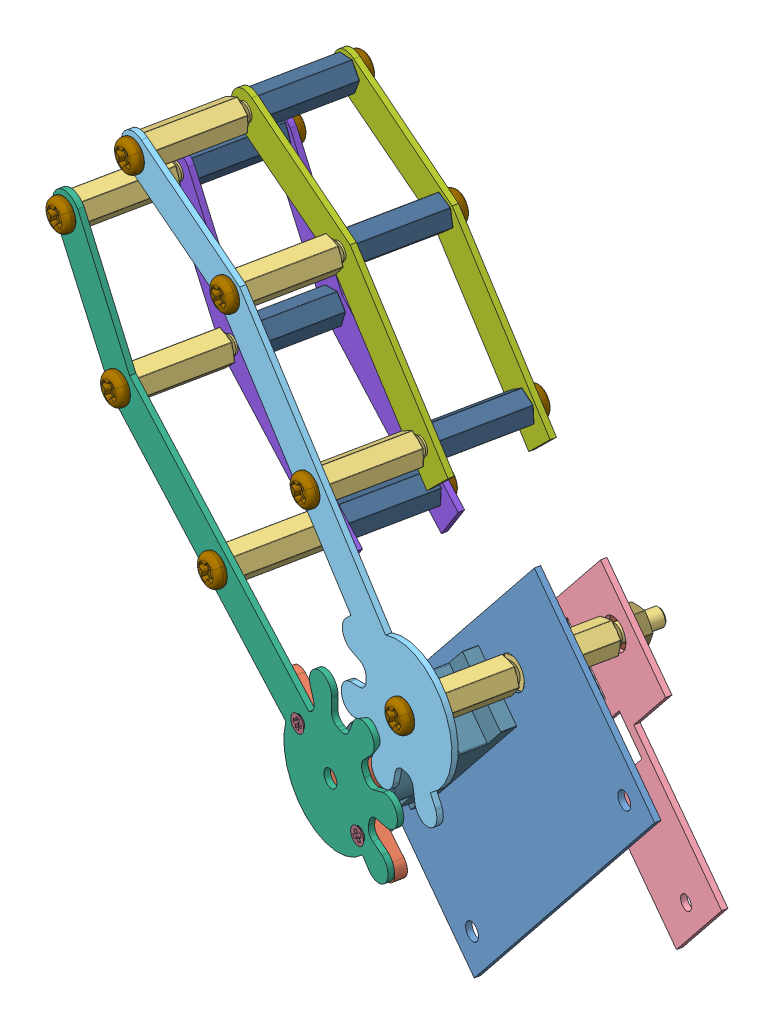
SolidWorks assembly Gripper, configuration Predeterminado. Lengths in mm.
Overall size (316.11 321.65 221.82).
47 component instances, 15 part files, 68 mates.
Components (placement in the parent):
- GripperBase-1: GripperBase [Predeterminado] at (70.7355 47.6147 -44.2967) x (-0.635673 -0.762927 -0.117736) z (-0.190799 0.007493 0.981601) size (64 37 1)
- Microservo horn-1: Microservo horn [По умолчанию] at (52.0643 33.1861 -30.7009) x (0.809028 -0.565128 0.161569) z (0.190799 -0.007493 -0.981601) size (32 7.5 5)
- HTSB-M3-15-5-2-2: HTSB-M3-15-5-2 [Predeterminado] at (71.8352 53.3676 -42.2931) x (-0.38875 0.917636 -0.082568) z (0.190799 -0.007493 -0.981601) size (5.74 5 23)
- HTSB-M3-15-5-2-3: HTSB-M3-15-5-2 [Predeterminado] at (74.888 53.2477 -57.9987) x (-0.73289 0.66416 -0.147525) z (0.190799 -0.007493 -0.981601) size (5.74 5 23)
- GripperBaseBottom-1: GripperBaseBottom [Predeterminado] at (73.7883 47.4949 -60.0023) x (-0.635673 -0.762927 -0.117736) z (-0.190799 0.007493 0.981601) size (51.3 47 1)
- finger1-2: finger1 [Predeterminado] at (8.4516 85.0486 -39.574) x (0.683757 -0.71647 0.138374) z (-0.190799 0.007493 0.981601) size (99.44 25.59 1)
- finger2-2: finger2 [Predeterminado] at (-5.5057 58.6647 -42.0855) x (0.809028 -0.565128 0.161569) z (-0.190799 0.007493 0.981601) size (100.44 26.59 1.27)
- finger1_short-1: finger1_short [Predeterminado] at (11.7524 84.919 -56.5557) x (0.683757 -0.71647 0.138374) z (-0.190799 0.007493 0.981601) size (58.27 15.95 1)
- finger1_short-2: finger1_short [Predeterminado] at (14.8052 84.7991 -72.2613) x (0.683757 -0.71647 0.138374) z (-0.190799 0.007493 0.981601) size (58.27 15.95 1)
- finger2_short-1: finger2_short [Predeterminado] at (-2.2049 58.535 -59.0672) x (0.809028 -0.565128 0.161569) z (-0.190799 0.007493 0.981601) size (58.27 15.95 1)
- finger2_short-2: finger2_short [Predeterminado] at (0.8479 58.4152 -74.7728) x (0.809028 -0.565128 0.161569) z (-0.190799 0.007493 0.981601) size (58.27 15.95 1)
- HTSB-M3-15-5-2-4: HTSB-M3-15-5-2 [Predeterminado] at (50.0233 76.223 -46.7072) x (-0.023499 0.999649 -0.012198) z (0.190799 -0.007493 -0.981601) size (5.74 5 23)
- HTSB-M3-15-5-2-6: HTSB-M3-15-5-2 [Predeterminado] at (31.22 95.9259 -50.5125) x (0.377161 -0.922655 0.080353) z (0.190799 -0.007493 -0.981601) size (5.74 5 23)
- HTSB-M3-15-5-2-7: HTSB-M3-15-5-2 [Predeterminado] at (29.1183 51.1013 -50.5789) x (0.594243 0.796807 0.109424) z (0.190799 -0.007493 -0.981601) size (5.74 5 23)
- HTSB-M3-15-5-2-9: HTSB-M3-15-5-2 [Predeterminado] at (6.87 66.6423 -55.0221) x (0.697683 0.70447 0.130235) z (0.190799 -0.007493 -0.981601) size (5.74 5 23)
- HTSB-M3-15-5-2-12: HTSB-M3-15-5-2 [Predeterminado] at (-5.7681 86.6747 -57.6315) x (-0.972238 0.136547 -0.190021) z (0.190799 -0.007493 -0.981601) size (5.74 5 23)
- HTSB-M3-15-5-2-15: HTSB-M3-15-5-2 [Predeterminado] at (9.6959 105.2228 -54.7673) x (-0.836425 0.522159 -0.166566) z (0.190799 -0.007493 -0.981601) size (5.74 5 23)
- M3x6 Philips Screw-1: M3x6 Philips Screw [Predeterminado] at (26.0464 51.2219 -34.7752) x (0.907999 -0.378629 0.179383) z (-0.190799 0.007493 0.981601) size (5.3 5.3 7.81)
- M3x6 Philips Screw-2: M3x6 Philips Screw [Predeterminado] at (68.7633 53.4882 -26.4893) x (0.907999 -0.378629 0.179383) z (-0.190799 0.007493 0.981601) size (5.3 5.3 7.81)
- M3x6 Philips Screw-3: M3x6 Philips Screw [Predeterminado] at (46.9515 76.3436 -30.9035) x (0.907999 -0.378629 0.179383) z (-0.190799 0.007493 0.981601) size (5.3 5.3 7.81)
- M3x6 Philips Screw-4: M3x6 Philips Screw [Predeterminado] at (3.7981 66.7629 -39.2183) x (0.907999 -0.378629 0.179383) z (-0.190799 0.007493 0.981601) size (5.3 5.3 7.81)
- M3x6 Philips Screw-5: M3x6 Philips Screw [Predeterminado] at (28.1863 96.045 -34.9051) x (0.907999 -0.378629 0.179383) z (-0.190799 0.007493 0.981601) size (5.3 5.3 7.81)
- M3x6 Philips Screw-6: M3x6 Philips Screw [Predeterminado] at (-8.84 86.7953 -41.8277) x (0.907999 -0.378629 0.179383) z (-0.190799 0.007493 0.981601) size (5.3 5.3 7.81)
- M3x6 Philips Screw-7: M3x6 Philips Screw [Predeterminado] at (6.624 105.3434 -38.9635) x (0.907999 -0.378629 0.179383) z (-0.190799 0.007493 0.981601) size (5.3 5.3 7.81)
- TFF-M3x15_DR113-1: TFF-M3x15_DR113 [Predeterminado] at (53.3242 76.0934 -63.6889) x (-0.190799 0.007493 0.981601) z (-0.978576 -0.080261 -0.189598) size (15 5.74 5)
- TFF-M3x15_DR113-2: TFF-M3x15_DR113 [Predeterminado] at (31.6589 95.9087 -52.7702) x (0.190799 -0.007493 -0.981601) z (0.65441 -0.744372 0.132883) size (15 5.74 5)
- TFF-M3x15_DR113-3: TFF-M3x15_DR113 [Predeterminado] at (10.1347 105.2056 -57.0249) x (0.190799 -0.007493 -0.981601) z (0.907999 -0.378629 0.179383) size (15 5.74 5)
- M3x6 Philips Screw-8: M3x6 Philips Screw [Predeterminado] at (53.534 76.0851 -64.7687) x (0.652004 0.748495 0.12102) z (0.190799 -0.007493 -0.981601) size (5.3 5.3 7.81)
- M3x6 Philips Screw-9: M3x6 Philips Screw [Predeterminado] at (34.7307 95.788 -68.574) x (0.802835 0.576592 0.15165) z (0.190799 -0.007493 -0.981601) size (5.3 5.3 7.81)
- M3x6 Philips Screw-10: M3x6 Philips Screw [Predeterminado] at (13.2066 105.085 -72.8287) x (0.313026 0.948231 0.053607) z (0.190799 -0.007493 -0.981601) size (5.3 5.3 7.81)
- TFF-M3x15_DR113-4: TFF-M3x15_DR113 [Predeterminado] at (48.9687 21.9505 -63.6129) x (-0.190799 0.007493 0.981601) z (0.24535 0.968597 0.040297) size (15 5.74 5)
- DIN_EN_ISO_7089_Plain_3.ipt-1: DIN_EN_ISO_7089_Plain_3.ipt [Predeterminado] at (75.3268 53.2305 -60.2564) x (0.902503 -0.39199 0.178416) z (-0.386114 -0.919939 -0.068029) size (7 0.5 7)
- M3 Nut1-1: M3 Nut1 [Predeterminado] at (75.0406 53.2417 -58.784) x (0.907999 -0.378629 0.179383) z (-0.190799 0.007493 0.981601) size (6.27 6.27 2.71)
- M3x6 Philips Screw-11: M3x6 Philips Screw [Predeterminado] at (49.1786 21.9423 -64.6926) x (-0.483773 -0.87082 -0.087386) z (0.190799 -0.007493 -0.981601) size (5.3 5.3 7.81)
- M3x6 Philips Screw-12: M3x6 Philips Screw [Predeterminado] at (45.8968 22.0711 -47.8091) x (0.907999 -0.378629 0.179383) z (-0.190799 0.007493 0.981601) size (5.3 5.3 7.81)
- TFF-M3x15_DR113-5: TFF-M3x15_DR113 [Predeterminado] at (7.3088 66.6251 -57.2797) x (0.190799 -0.007493 -0.981601) z (0.73427 0.664756 0.13765) size (15 5.74 5)
- TFF-M3x15_DR113-6: TFF-M3x15_DR113 [Predeterminado] at (-5.3293 86.6574 -59.8892) x (0.190799 -0.007493 -0.981601) z (0.058954 0.998253 0.00384) size (15 5.74 5)
- TFF-M3x15_DR113-7: TFF-M3x15_DR113 [Predeterminado] at (29.5571 51.0841 -52.8366) x (0.190799 -0.007493 -0.981601) z (0.538616 0.836796 0.098306) size (15 5.74 5)
- M3x6 Philips Screw-13: M3x6 Philips Screw [Predeterminado] at (32.629 50.9634 -68.6404) x (0.770968 -0.617831 0.154573) z (0.190799 -0.007493 -0.981601) size (5.3 5.3 7.81)
- M3x6 Philips Screw-14: M3x6 Philips Screw [Predeterminado] at (10.3807 66.5045 -73.0835) x (0.598591 -0.791649 0.122394) z (0.190799 -0.007493 -0.981601) size (5.3 5.3 7.81)
- M3x6 Philips Screw-15: M3x6 Philips Screw [Predeterminado] at (-2.2574 86.5368 -75.6929) x (0.979927 0.060321 0.190013) z (0.190799 -0.007493 -0.981601) size (5.3 5.3 7.81)
- (M2_3_mm)_90116A007_METRIC 316 SS PAN HEAD PHILLIPS MACHINE SCREW-1: (M2_3_mm)_90116A007_METRIC 316 SS PAN HEAD PHILLIPS MACHINE SCREW [90116A007] at (52.4459 33.1711 -32.6641) x (0.917047 -0.355355 0.180964) z (-0.190799 0.007493 0.981601) size (4 4 4.68) (hidden)
- M2x6 SelfTap Screw-1: M2x6 SelfTap Screw [Predeterminado] at (58.6548 28.3938 -27.8551) x (0.539771 -0.834424 0.111287) z (-0.190799 0.007493 0.981601) size (3.4 3.28 6)
- M2x6 SelfTap Screw-2: M2x6 SelfTap Screw [Predeterminado] at (44.9014 38.0009 -30.6018) x (0.977292 -0.092444 0.190667) z (-0.190799 0.007493 0.981601) size (3.4 3.28 6)
- M2x6 SelfTap Screw-3: M2x6 SelfTap Screw [Predeterminado] at (49.2304 26.7579 -44.2426) x (0.886617 -0.427872 0.175602) z (-0.190799 0.007493 0.981601) size (3.4 3.28 6)
- M2x6 SelfTap Screw-4: M2x6 SelfTap Screw [Predeterminado] at (66.5843 47.5858 -41.0284) x (0.886617 -0.427872 0.175602) z (-0.190799 0.007493 0.981601) size (3.4 3.28 6)
- sg90-3: sg90 [Default] at (49.9489 32.2613 -63.3992) x (0.635673 0.762927 0.117736) z (0.748008 -0.646441 0.150328) size (373.87 165 11.8)
Mates (geometry in assembly coordinates):
- Concéntrica7: concentric: circle of HTSB-M3-15-5-2-3; circle of GripperBaseBottom-1
- Coincidente26: coincident: plane of HTSB-M3-15-5-2-2 through (70.0954 50.831 -27.3308) normal (-0.190799 0.007493 0.981601); plane of finger1-2 through (6.8339 105.3352 -40.0433) normal (0.190799 -0.007493 -0.981601)
- Concéntrica11: concentric: circle of HTSB-M3-15-5-2-2; circle of finger1-2
- Coincidente30: coincident: plane of Microservo horn-1 through (52.0643 33.1861 -30.7009) normal (-0.190799 0.007493 0.981601); plane of finger2-2 through (59.3957 44.0654 -29.3589) normal (0.190799 -0.007493 -0.981601)
- Coincidente40: coincident: plane of finger1-2 through (6.8339 105.3352 -40.0433) normal (0.190799 -0.007493 -0.981601); plane of HTSB-M3-15-5-2-4 through (47.2292 73.4496 -31.948) normal (-0.190799 0.007493 0.981601)
- Concéntrica17: concentric: circle of finger1-2; circle of HTSB-M3-15-5-2-4
- Distancia6: distance = 0.5 mm: plane of GripperBase-1 through (70.7355 47.6147 -44.2967) normal (0.190799 -0.007493 -0.981601); plane of finger1_short-1 through (9.9439 105.2131 -56.0433) normal (-0.190799 0.007493 0.981601)
- Concéntrica21: concentric: circle of finger1-2; circle of HTSB-M3-15-5-2-6
- Coincidente51: coincident: plane of finger1-2 through (6.8339 105.3352 -40.0433) normal (0.190799 -0.007493 -0.981601); plane of HTSB-M3-15-5-2-6 through (27.2693 98.7018 -36.0205) normal (-0.190799 0.007493 0.981601)
- Coincidente56: coincident: plane of finger2-2 through (59.3957 44.0654 -29.3589) normal (0.190799 -0.007493 -0.981601); plane of HTSB-M3-15-5-2-7 through (24.5408 48.9135 -36.1708) normal (-0.190799 0.007493 0.981601)
- Concéntrica25: concentric: circle of finger2-2; circle of HTSB-M3-15-5-2-7
- Concéntrica26: concentric: circle of finger2_short-1; circle of HTSB-M3-15-5-2-7
- Coincidente59: coincident: plane of finger1_short-1 through (9.9439 105.2131 -56.0433) normal (-0.190799 0.007493 0.981601); plane of finger2_short-1 through (-5.5201 86.6649 -58.9076) normal (-0.190799 0.007493 0.981601)
- Concéntrica27: concentric: circle of finger2-2; circle of HTSB-M3-15-5-2-9
- Coincidente61: coincident: plane of finger2-2 through (59.3957 44.0654 -29.3589) normal (0.190799 -0.007493 -0.981601); plane of HTSB-M3-15-5-2-9 through (1.994 64.7211 -40.674) normal (-0.190799 0.007493 0.981601)
- Concéntrica28: concentric: circle of finger2_short-1; circle of HTSB-M3-15-5-2-9
- Coincidente63: coincident: plane of finger1_short-2 through (12.9967 105.0932 -71.749) normal (-0.190799 0.007493 0.981601); plane of finger2_short-2 through (-2.4673 86.545 -74.6132) normal (-0.190799 0.007493 0.981601)
- Concéntrica29: concentric: circle of finger2_short-2; circle of HTSB-M3-15-5-2-9
- Concéntrica32: concentric: circle of finger2_short-1; circle of finger2_short-2
- Concéntrica33: concentric: circle of finger1_short-1; circle of HTSB-M3-15-5-2-4
- Coincidente72: coincident: plane of finger1-2 through (6.8339 105.3352 -40.0433) normal (0.190799 -0.007493 -0.981601); plane of HTSB-M3-15-5-2-15 through (9.2484 103.8279 -39.5624) normal (-0.190799 0.007493 0.981601)
- Concéntrica34: concentric: circle of finger1-2; circle of HTSB-M3-15-5-2-15
- Coincidente76: coincident: plane of finger2-2 through (59.3957 44.0654 -29.3589) normal (0.190799 -0.007493 -0.981601); plane of HTSB-M3-15-5-2-12 through (-5.8235 86.3929 -42.3589) normal (-0.190799 0.007493 0.981601)
- Concéntrica36: concentric: circle of finger2-2; circle of HTSB-M3-15-5-2-12
- Concéntrica38: concentric: circle of finger2_short-1; circle of HTSB-M3-15-5-2-12
- Coincidente91: coincident: plane of finger1_short-1 through (10.1347 105.2056 -57.0249) normal (0.190799 -0.007493 -0.981601); plane of TFF-M3x15_DR113-1 through (50.4622 76.2057 -48.9649) normal (-0.190799 0.007493 0.981601)
- Concéntrica47: concentric: circle of HTSB-M3-15-5-2-4; circle of TFF-M3x15_DR113-1
- Coincidente92: coincident: plane of finger1_short-1 through (10.1347 105.2056 -57.0249) normal (0.190799 -0.007493 -0.981601); plane of TFF-M3x15_DR113-2 through (31.6589 95.9087 -52.7702) normal (-0.190799 0.007493 0.981601)
- Concéntrica48: concentric: circle of HTSB-M3-15-5-2-6; circle of TFF-M3x15_DR113-2
- Coincidente93: coincident: plane of finger1_short-1 through (10.1347 105.2056 -57.0249) normal (0.190799 -0.007493 -0.981601); plane of TFF-M3x15_DR113-3 through (10.1347 105.2056 -57.0249) normal (-0.190799 0.007493 0.981601)
- Concéntrica49: concentric: circle of HTSB-M3-15-5-2-15; circle of TFF-M3x15_DR113-3
- Coincidente96: coincident: plane of finger1_short-2 through (12.9967 105.0932 -71.749) normal (-0.190799 0.007493 0.981601); plane of TFF-M3x15_DR113-1 through (53.3242 76.0934 -63.6889) normal (0.190799 -0.007493 -0.981601)
- Concéntrica53: concentric: circle of HTSB-M3-15-5-2-3; circle of DIN_EN_ISO_7089_Plain_3.ipt-1
- Coincidente101: coincident: plane of GripperBaseBottom-1 through (73.7883 47.4949 -60.0023) normal (0.190799 -0.007493 -0.981601); plane of DIN_EN_ISO_7089_Plain_3.ipt-1 through (75.2314 53.2342 -59.7656) normal (-0.190799 0.007493 0.981601)
- Coincidente102: coincident: plane of DIN_EN_ISO_7089_Plain_3.ipt-1 through (75.3268 53.2305 -60.2564) normal (0.190799 -0.007493 -0.981601); plane of M3 Nut1-1 through (75.3268 53.2305 -60.2564) normal (-0.190799 0.007493 0.981601)
- Concéntrica54: concentric: circle of HTSB-M3-15-5-2-3; circle of M3 Nut1-1
- Coincidente103: coincident: plane of GripperBase-1 through (70.7355 47.6147 -44.2967) normal (0.190799 -0.007493 -0.981601); plane of TFF-M3x15_DR113-4 through (46.1067 22.0629 -48.8889) normal (-0.190799 0.007493 0.981601)
- Concéntrica55: concentric: circle of GripperBase-1; circle of TFF-M3x15_DR113-4
- Coincidente106: coincident: plane of finger2_short-1 through (-5.3293 86.6574 -59.8892) normal (0.190799 -0.007493 -0.981601); plane of TFF-M3x15_DR113-7 through (29.5571 51.0841 -52.8366) normal (-0.190799 0.007493 0.981601)
- Concéntrica58: concentric: circle of HTSB-M3-15-5-2-7; circle of TFF-M3x15_DR113-7
- Concéntrica59: concentric: circle of HTSB-M3-15-5-2-9; circle of TFF-M3x15_DR113-5
- Coincidente107: coincident: plane of finger2_short-1 through (-5.3293 86.6574 -59.8892) normal (0.190799 -0.007493 -0.981601); plane of TFF-M3x15_DR113-5 through (7.3088 66.6251 -57.2797) normal (-0.190799 0.007493 0.981601)
- Coincidente108: coincident: plane of finger2_short-1 through (-5.3293 86.6574 -59.8892) normal (0.190799 -0.007493 -0.981601); plane of TFF-M3x15_DR113-6 through (-5.3293 86.6574 -59.8892) normal (-0.190799 0.007493 0.981601)
- Concéntrica60: concentric: circle of HTSB-M3-15-5-2-12; circle of TFF-M3x15_DR113-6
- Coincidente121: coincident: circle of HTSB-M3-15-5-2-2; plane of HTSB-M3-15-5-2-3 through (74.1416 51.4428 -42.8488) normal (-0.190799 0.007493 0.981601)
- Coincidente122: coincident: plane of GripperBaseBottom-1 through (73.5975 47.5023 -59.0207) normal (-0.190799 0.007493 0.981601); plane of TFF-M3x15_DR113-4 through (48.9687 21.9505 -63.6129) normal (0.190799 -0.007493 -0.981601)
- Concéntrica77: concentric: circle of GripperBaseBottom-1; circle of TFF-M3x15_DR113-4
- Concéntrica78: concentric: circle of finger1_short-1; circle of TFF-M3x15_DR113-3
- Concéntrica80: concentric: circle of Microservo horn-1; circle of finger2-2
- Concéntrica82: concentric: circle of finger2-2; circle of (M2_3_mm)_90116A007_METRIC 316 SS PAN HEAD PHILLIPS MACHINE SCREW-1
- Coincidente124: coincident: plane of finger2-2 through (59.2049 44.0729 -28.3773) normal (-0.190799 0.007493 0.981601); plane of (M2_3_mm)_90116A007_METRIC 316 SS PAN HEAD PHILLIPS MACHINE SCREW-1 through (51.8735 33.1936 -29.7193) normal (0.190799 -0.007493 -0.981601)
- Concéntrica87: concentric: circle of finger2-2; circle of M2x6 SelfTap Screw-1
- Concéntrica88: concentric: circle of finger2-2; circle of M2x6 SelfTap Screw-2
- Distancia26: distance = 0.5 mm: plane of M2x6 SelfTap Screw-1 through (58.6548 28.3938 -27.8551) normal (-0.190799 0.007493 0.981601); plane of finger2-2 through (59.2049 44.0729 -28.3773) normal (-0.190799 0.007493 0.981601)
- Distancia27: distance = 0.5 mm: plane of M2x6 SelfTap Screw-2 through (44.9014 38.0009 -30.6018) normal (-0.190799 0.007493 0.981601); plane of finger2-2 through (59.2049 44.0729 -28.3773) normal (-0.190799 0.007493 0.981601)
- Concéntrica90: concentric: circle of GripperBase-1; circle of HTSB-M3-15-5-2-2
- Concéntrica91: concentric: circle of Microservo horn-1; circle of finger2-2
- Concéntrica94: concentric: circle of GripperBase-1; circle of HTSB-M3-15-5-2-3
- Coincidente131: coincident: plane of GripperBase-1 through (61.2178 49.5463 -45.1427) normal (0.748008 -0.646441 0.150328); plane of sg90-3 through (49.9489 32.2613 -63.3992) normal (-0.748008 0.646441 -0.150328)
- Coincidente132: coincident: plane of GripperBase-1 through (70.0443 41.9183 -43.3688) normal (-0.635673 -0.762927 -0.117736); plane of sg90-3 through (73.078 41.7992 -58.9763) normal (0.635673 0.762927 0.117736)
- Coincidente133: coincident: line of GripperBase-1 through (104.4446 48.9241 -36.7357) axis (-0.748008 0.646441 -0.150328); plane of sg90-3 through (43.9275 28.7947 -48.3451) normal (0.190799 -0.007493 -0.981601)
- Concéntrica96: concentric: circle of Microservo horn-1; circle of sg90-3
- Coincidente135: coincident: plane of Microservo horn-1 through (53.0183 33.1486 -35.6089) normal (0.190799 -0.007493 -0.981601); plane of sg90-3 through (53.0183 33.1486 -35.6089) normal (-0.190799 0.007493 0.981601)
- Coincidente137: coincident: plane of finger1-2 through (6.6431 105.3427 -39.0617) normal (-0.190799 0.007493 0.981601); plane of finger2-2 through (59.2049 44.0729 -28.3773) normal (-0.190799 0.007493 0.981601)
- Concéntrica97: concentric: circle of M2x6 SelfTap Screw-3; circle of sg90-3
- Concéntrica98: concentric: circle of M2x6 SelfTap Screw-4; circle of sg90-3
- Distancia28: distance = 0.5 mm: plane of M2x6 SelfTap Screw-3 through (49.2304 26.7579 -44.2426) normal (-0.190799 0.007493 0.981601); plane of sg90-3 through (43.4505 28.8134 -45.8911) normal (-0.190799 0.007493 0.981601)
- Distancia29: distance = 0.5 mm: plane of M2x6 SelfTap Screw-4 through (66.5843 47.5858 -41.0284) normal (-0.190799 0.007493 0.981601); plane of sg90-3 through (72.555 45.5228 -40.3615) normal (-0.190799 0.007493 0.981601)
